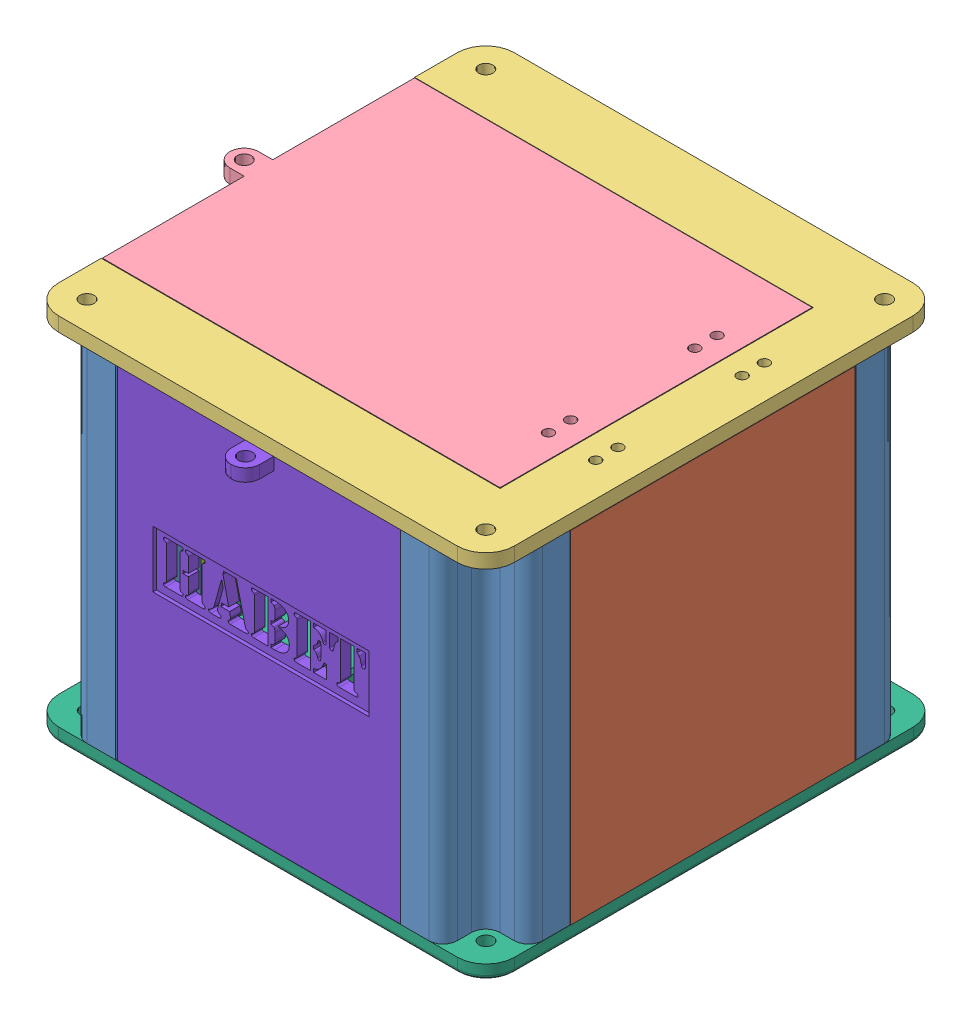
SolidWorks assembly TriplerBoxassembly, configuration Default. Lengths in mm.
Overall size (216.1 165.1 216.07).
11 component instances, 8 part files, 27 mates.
Components (placement in the parent):
- pylons-1: pylons [Default] at (-5.5441 271.8772 116.7145) x (0 0 1) z (0 -1 0) size (38.1 38.1 155.57)
- pylons-2: pylons [Default] at (-5.5441 271.8772 -10.2855) x (-1 0 0) z (0 -1 0) size (38.1 38.1 155.57)
- pylons-3: pylons [Default] at (121.4559 271.8772 -10.2855) x (0 0 -1) z (0 -1 0) size (38.1 38.1 155.57)
- pylons-4: pylons [Default] at (121.4559 271.8772 116.7145) x (1 0 0) z (0 -1 0) size (38.1 38.1 155.57)
- Realwall-2: Realwall [Default] at (153.4059 119.4772 123.5725) x (0 0 -1) z (0 -1 0) size (139.5 6.35 152.4)
- top-1: top [Default] at (-43.6441 271.8772 -10.2855) size (203.2 19.05 203.2)
- lid-1: lid [Default] at (133.6479 278.0272 -16.6355) x (0 0 1) z (1 0 0) size (139.19 6.35 189.99)
- DiscAntennawall-1: DiscAntennawall [Default] at (-12.4021 271.8772 -42.3352) x (1 0 0) z (0 1 0) size (139.4 6.35 152.4)
- BaseTripler-1: BaseTripler [Default] at (-43.5463 113.1272 154.8145) size (203.2 19.05 203.2)
- antennaholewall-2: antennaholewall [Default] at (-37.5938 119.2772 -15.8278) x (0 0 1) z (0 -1 0) size (139.4 6.35 152.4)
- Frontwall-2: Frontwall [Default] at (-11.0863 119.4772 148.3375) x (1 0 0) z (0 -1 0) size (139.4 19.05 152.4)
Mates (geometry in assembly coordinates):
- Coincident19: coincident anti-aligned: plane of pylons-4 through (156.3809 271.8772 123.5725) normal (0 0 -1); plane of Realwall-2 through (159.7559 119.4772 123.5725) normal (0 0 1)
- Coincident20: coincident anti-aligned: plane of pylons-4 through (156.3809 271.8772 116.7145) normal (-1 0 0); plane of Realwall-2 through (156.3809 119.4772 123.5725) normal (1 0 0)
- Concentric6: concentric anti-aligned: cylinder of pylons-1 through (-15.0691 271.8772 126.2395) axis (0 -1 0) radius 4.953; cylinder of top-1 through (-15.0691 259.1772 126.2395) axis (0 1 0) radius 4.6625
- Concentric7: concentric anti-aligned: cylinder of pylons-2 through (-15.0691 271.8772 -19.8105) axis (0 -1 0) radius 4.953; cylinder of top-1 through (-15.0691 259.1772 -19.8105) axis (0 1 0) radius 4.6625
- Coincident26: coincident anti-aligned: plane of top-1 through (-43.6441 275.0522 -10.2855) normal (0 1 0); plane of lid-1 through (133.6479 275.0522 -16.6355) normal (0 -1 0)
- Coincident27: coincident anti-aligned: plane of top-1 through (134.1559 275.0522 -16.6355) normal (0 0 1); plane of lid-1 through (133.6479 271.6772 -16.6355) normal (0 0 -1)
- Coincident33: coincident anti-aligned: plane of pylons-2 through (-5.5441 271.8772 -45.2105) normal (0 0 1); plane of DiscAntennawall-1 through (-12.4021 271.8772 -45.2105) normal (0 0 -1)
- Coincident34: coincident anti-aligned: plane of pylons-2 through (-12.4021 271.8772 -45.2105) normal (1 0 0); plane of DiscAntennawall-1 through (-12.4021 271.8772 -48.6852) normal (-1 0 0)
- Concentric8: concentric anti-aligned: cylinder of pylons-4 through (130.9809 271.8772 126.2395) axis (0 -1 0) radius 4.953; cylinder of top-1 through (130.9809 259.1772 126.2395) axis (0 1 0) radius 4.6625
- Concentric9: concentric anti-aligned: cylinder of pylons-3 through (130.9809 271.8772 -19.8105) axis (0 -1 0) radius 4.953; cylinder of top-1 through (130.9809 259.1772 -19.8105) axis (0 1 0) radius 4.6625
- Concentric10: concentric anti-aligned: cylinder of pylons-2 through (-15.0691 271.8772 -19.8105) axis (0 -1 0) radius 4.953; cylinder of top-1 through (-15.0691 259.1772 -19.8105) axis (0 1 0) radius 4.6625
- Coincident35: coincident aligned: plane of top-1 through (-43.6441 278.2272 142.1145) normal (-1 0 0); plane of lid-1 through (-43.6441 271.6772 -16.6355) normal (-1 0 0)
- Coincident36: coincident anti-aligned: plane of pylons-1 through (-5.5441 271.8772 116.7145) normal (0 1 0); plane of top-1 through (-30.9441 271.8772 -35.6855) normal (0 -1 0)
- Coincident37: coincident anti-aligned: plane of pylons-4 through (121.4559 271.8772 116.7145) normal (0 1 0); plane of top-1 through (-30.9441 271.8772 -35.6855) normal (0 -1 0)
- Coincident38: coincident anti-aligned: plane of pylons-3 through (121.4559 271.8772 -10.2855) normal (0 1 0); plane of top-1 through (-30.9441 271.8772 -35.6855) normal (0 -1 0)
- Coincident39: coincident anti-aligned: plane of pylons-2 through (-5.5441 271.8772 -10.2855) normal (0 1 0); plane of top-1 through (-30.9441 271.8772 -35.6855) normal (0 -1 0)
- Coincident40: coincident anti-aligned: plane of top-1 through (-30.9441 271.8772 -35.6855) normal (0 -1 0); plane of DiscAntennawall-1 through (-12.4021 271.8772 -48.6852) normal (0 1 0)
- Coincident41: coincident anti-aligned: plane of Realwall-2 through (159.7559 271.8772 123.5725) normal (0 1 0); plane of top-1 through (-30.9441 271.8772 -35.6855) normal (0 -1 0)
- Coincident42: coincident anti-aligned: plane of pylons-1 through (-24.5941 116.3022 123.6873) normal (-0.707107 0 -0.707107); plane of BaseTripler-1 through (-17.5442 116.3022 116.6374) normal (0.707107 0 0.707107)
- Coincident43: coincident anti-aligned: plane of pylons-2 through (-17.6213 116.3022 -10.2855) normal (-0.707107 0 0.707107); plane of BaseTripler-1 through (-17.5442 116.3022 -10.2084) normal (0.707107 0 -0.707107)
- Coincident44: coincident anti-aligned: plane of pylons-2 through (-5.5441 119.4772 -10.2855) normal (0 -1 0); plane of BaseTripler-1 through (-43.5463 119.4772 154.8145) normal (0 1 0)
- Coincident45: coincident anti-aligned: plane of BaseTripler-1 through (-43.5463 119.4772 154.8145) normal (0 1 0); plane of Frontwall-2 through (-11.0863 119.4772 154.6875) normal (0 -1 0)
- Coincident46: coincident anti-aligned: plane of pylons-4 through (128.3139 271.8772 151.6395) normal (-1 0 0); plane of Frontwall-2 through (128.3139 119.4772 154.6875) normal (1 0 0)
- Coincident47: coincident anti-aligned: plane of pylons-4 through (121.4559 271.8772 148.3375) normal (0 0 1); plane of Frontwall-2 through (-11.0863 119.4772 148.3375) normal (0 0 -1)
- Coincident48: coincident anti-aligned: plane of lid-1 through (133.6479 271.6772 -16.6355) normal (0 -1 0); plane of antennaholewall-2 through (-43.9438 271.6772 -15.8278) normal (0 1 0)
- Coincident49: coincident anti-aligned: plane of pylons-1 through (-40.4691 271.8772 116.7145) normal (1 0 0); plane of antennaholewall-2 through (-40.4691 119.2772 -15.8278) normal (-1 0 0)
- Coincident50: coincident anti-aligned: plane of pylons-1 through (-40.4691 271.8772 123.5725) normal (0 0 -1); plane of antennaholewall-2 through (-43.9438 119.2772 123.5725) normal (0 0 1)
